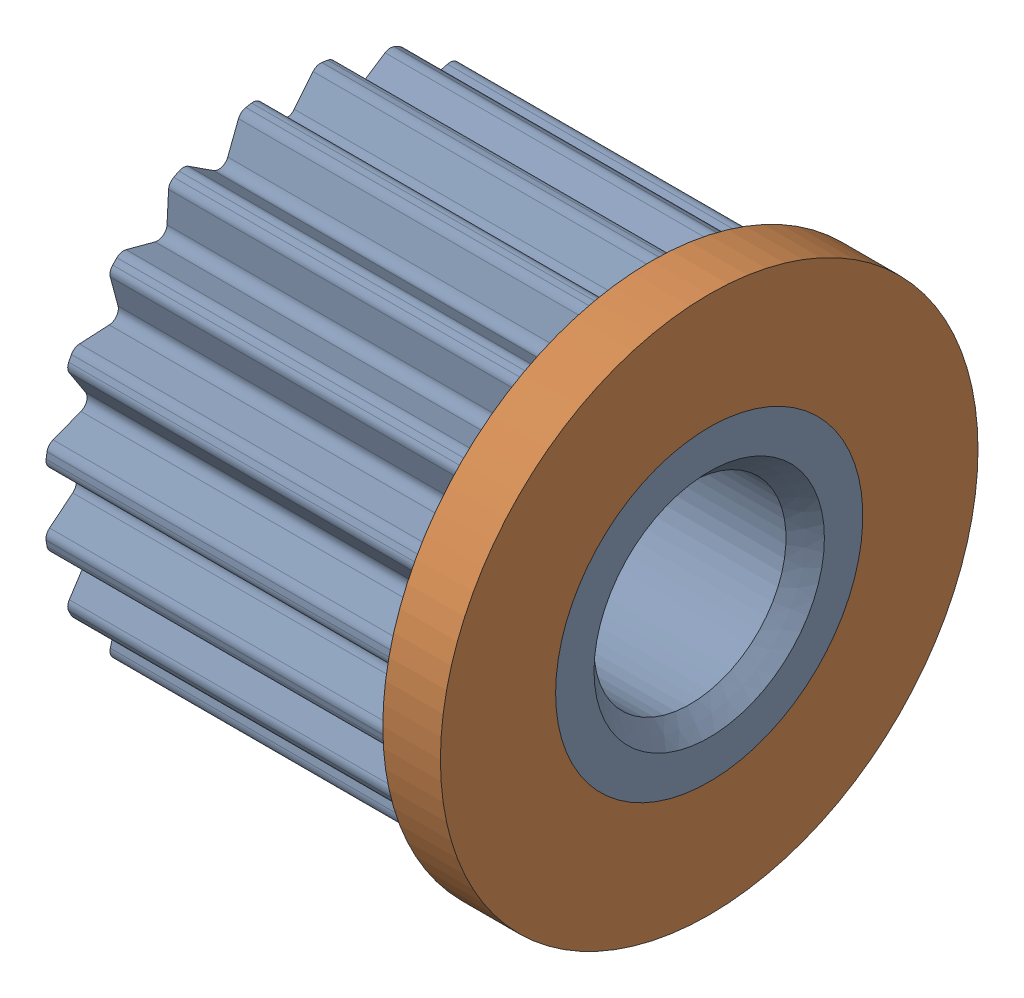
SolidWorks assembly poulie motrice, configuration Défaut. Lengths in mm.
Overall size (11 14 14).
2 component instances, 2 part files, 1 mates.
Components (placement in the parent):
- poulie motrice Z=20-1: poulie motrice Z=20 [Défaut] at origin size (11 12.54 12.54)
- Flasque poulie-1: Flasque poulie [Défaut] at (-16.112 -39.2783 0) size (1.5 14 14)
Mates (geometry in assembly coordinates):
- Coïncidente1: coincident: circle of poulie motrice Z=20-1 centre (-24.225 -11.3829 0) axis (-1 0 0); circle of Flasque poulie-1 centre (-24.225 -11.3829 0) axis (-1 0 0)
